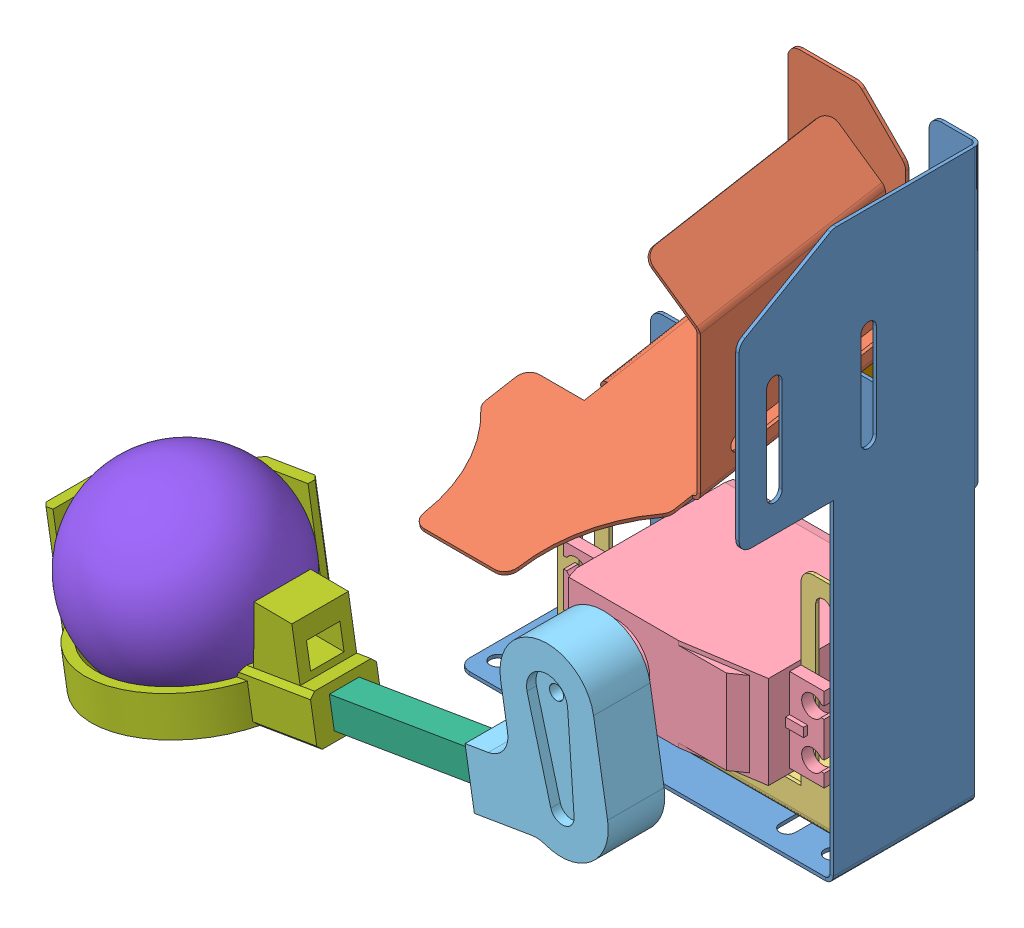
SolidWorks assembly 00 Ball Handler, configuration Default. Lengths in mm.
Overall size (153.3 158.6 97.81).
11 component instances, 9 part files, 11 mates.
Components (placement in the parent):
- Base Plate-1: Base Plate [Default] at (0 0.7 0) size (79.7 120.7 51.7)
- Upper Ramp-1: Upper Ramp [Default] at (7.3 85.5855 50.0026) x (0 -0.173648 0.984808) z (-1 0 0) size (83.47 47.51 41.7)
- 01 Lifting Assembly-2: 01 Lifting Assembly [Default] at (-5 0.7 22.5) size (149.95 72.24 64.44) (flexible)
  - Lifting Servo Bracket-1: Lifting Servo Bracket [Default] at (0 24.2 0) size (62.7 46.7 15.7)
  - Servo Futaba S3003-1: Servo Futaba S3003 [Default] at (0.03 20 9.4742) x (0 -1 0) z (0 0 -1) size (19.69 55.27 37.39)
  - 02 Arm Assembly-1: 02 Arm Assembly [Default] at (-9.4315 20 24.0998) x (-0.986262 -0.16519 0) z (0 0 1) size (118.5 41.05 43.5)
    - Arm-Servo Mount-1: Arm-Servo Mount [Default] at origin size (30 38 12)
    - Arm Rod-1: Arm Rod [Default] at (0 19.95 -5.95) x (0 -1 0) z (0 0 1) size (6.3 64.5 6.3)
    - Arm Hoop-1: Arm Hoop [Default] at (85 24.95 -5.95) x (0 0 -1) z (0 -1 0) size (43.5 56 25)
    - SquashBall-1: SquashBall [Default] at (85 6.95 -5.95) size (40 40 40)
- Corner Brace-2: Corner Brace [Default] at (28 55.7 -2.4) x (0 -1 0) z (0 0 -1) size (31.46 31.46 0.7)
Mates (geometry in assembly coordinates):
- Coincident1: coincident anti-aligned: plane of Base Plate-1 through (0 0 0) normal (0 -1 0); plane of assembly through (0 0 0) normal (0 1 0)
- Coincident2: coincident aligned: plane of Base Plate-1 through (0 0.7 0) normal (0 0 1); plane of assembly through (0 0 0) normal (0 0 1)
- Coincident3: coincident aligned: plane of Base Plate-1 through (0 0.7 0) normal (1 0 0); plane of assembly through (0 0 0) normal (1 0 0)
- Coincident5: coincident anti-aligned: plane of Base Plate-1 through (0 0.7 0) normal (0 1 0); plane of 01 Lifting Assembly-2/Lifting Servo Bracket-1 through (-5 0.7 22.5) normal (0 -1 0)
- Parallel1: parallel aligned: plane of 01 Lifting Assembly-2 through (-5 0.7 22.5) normal (0 0 1); plane of assembly through (0 0 0) normal (0 0 1)
- Distance1: distance = 7.5 mm aligned: plane of 01 Lifting Assembly-2/Lifting Servo Bracket-1 through (-5 24.9 22.5) normal (0 0 1); line of Base Plate-1 through (-47.5 0.7 30) axis (1 0 0)
- Tangent1: tangent anti-aligned: plane of Base Plate-1 through (13.35 -0.001 5) normal (1 0 0); cylinder of 01 Lifting Assembly-2/Lifting Servo Bracket-1 through (15 0.699 13.8) axis (0 1 0) radius 1.65
- Coincident15: coincident anti-aligned: plane of Base Plate-1 through (0 0.7 -1.7) normal (0 0 -1); plane of Corner Brace-2 through (28 55.7 -1.7) normal (0 0 1)
- Coincident16: coincident anti-aligned: line of Base Plate-1 through (28 58.9913 -1.7) axis (0 1 0); line of Corner Brace-2 through (28 84.6645 -1.7) axis (0 -1 0)
- Coincident17: coincident anti-aligned: line of Base Plate-1 through (-37.608 55.7 -1.7) axis (1 0 0); line of Corner Brace-2 through (25.5 55.7 -1.7) axis (-1 0 0)
- Coincident18: coincident anti-aligned: plane of Base Plate-1 through (29 0.7 0) normal (-1 0 0); plane of Upper Ramp-1 through (29 85.5855 50.0026) normal (1 0 0)
